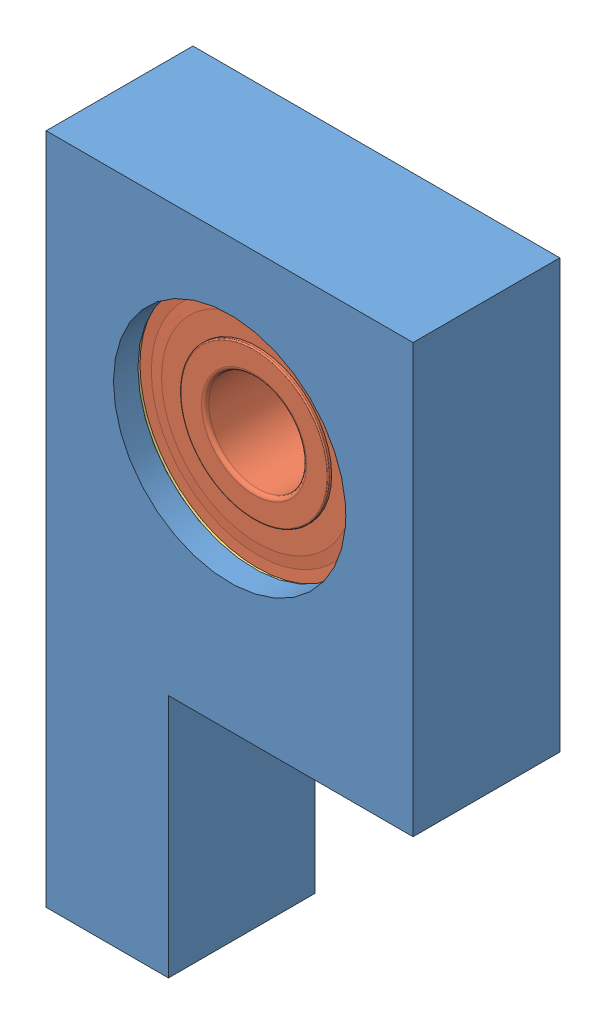
SolidWorks assembly Lagerbock_assembled, configuration Standard. Lengths in mm.
Overall size (30 55 12).
18 component instances, 5 part files, 1 mates.
Components (placement in the parent):
- Lagerbock-1: Lagerbock [Standard] at (0.8863 -1.2135 34) size (30 55 12)
- 608-2Z-1: 608-2Z [Standard] at (0.8863 -1.2135 44) x (0 0 -1) z (1 0 0) size (7 22 22)
  - 608-2Z_PART1-1: 608-2Z_PART1 [Standard] at origin size (7 19.2 19.2)
  - 608-2Z_PART2-1: 608-2Z_PART2 [Standard] at origin size (7 22 22)
  - 608-2Z_PART3-1: 608-2Z_PART3 [Standard] at origin size (3.97 3.97 3.97)
  - 608-2Z_PART3-2: 608-2Z_PART3 [Standard] x (1 0 0) z (0 0.781831 0.62349) size (3.97 3.97 3.97)
  - 608-2Z_PART3-3: 608-2Z_PART3 [Standard] x (1 0 0) z (0 0.974928 -0.222521) size (3.97 3.97 3.97)
  - 608-2Z_PART3-4: 608-2Z_PART3 [Standard] x (1 0 0) z (0 0.433884 -0.900969) size (3.97 3.97 3.97)
  - 608-2Z_PART3-5: 608-2Z_PART3 [Standard] x (1 0 0) z (0 -0.433884 -0.900969) size (3.97 3.97 3.97)
  - 608-2Z_PART3-6: 608-2Z_PART3 [Standard] x (1 0 0) z (0 -0.974928 -0.222521) size (3.97 3.97 3.97)
  - 608-2Z_PART3-7: 608-2Z_PART3 [Standard] x (1 0 0) z (0 -0.781831 0.62349) size (3.97 3.97 3.97)
  - 608-2Z_PART4-1: 608-2Z_PART4 [Standard] at origin
  - 608-2Z_PART4-2: 608-2Z_PART4 [Standard] x (1 0 0) z (0 0.781831 0.62349)
  - 608-2Z_PART4-3: 608-2Z_PART4 [Standard] x (1 0 0) z (0 0.974928 -0.222521)
  - 608-2Z_PART4-4: 608-2Z_PART4 [Standard] x (1 0 0) z (0 0.433884 -0.900969)
  - 608-2Z_PART4-5: 608-2Z_PART4 [Standard] x (1 0 0) z (0 -0.433884 -0.900969)
  - 608-2Z_PART4-6: 608-2Z_PART4 [Standard] x (1 0 0) z (0 -0.974928 -0.222521)
  - 608-2Z_PART4-7: 608-2Z_PART4 [Standard] x (1 0 0) z (0 -0.781831 0.62349)
Mates (geometry in assembly coordinates):
- Konzentrisch1: concentric anti-aligned: cylinder of Lagerbock-1 through (0.8863 -1.2135 44) axis (0 0 -1) radius 11; cylinder of 608-2Z-1/608-2Z_PART2-1 through (0.8863 -1.2135 -6) axis (0 0 1) radius 11
